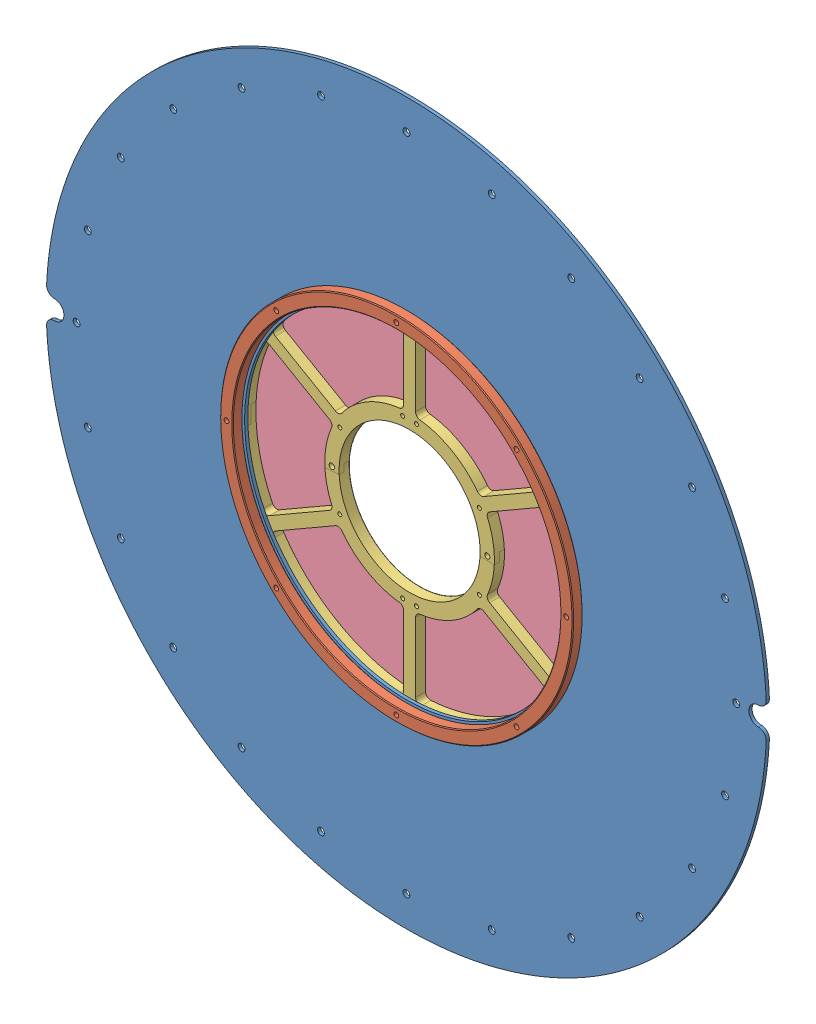
SolidWorks assembly IDS OSC Stiffener (West) ASSY, configuration Default. Lengths in mm.
Overall size (453.86 454.4 14.75).
6 component instances, 5 part files, 11 mates.
Components (placement in the parent):
- IDS OSC Stiffener (West)-1: IDS OSC Stiffener (West) [Default] at origin size (453.86 454.4 2)
- IDS Viton Disk-1: IDS Viton Disk [Default] at (0 0 -0.5) x (-0.55065 -0.834736 0) z (0 0 -1) (suppressed, hidden)
- IDS WSC Cooling Tube Support Ring-1: IDS WSC Cooling Tube Support Ring [Default] at (0 0 2) size (222.5 222.5 6.35)
- IDS WSC West Beampipe Support-1: IDS WSC West Beampipe Support [Default] at (0 0 -3.175) size (222 116.81 6.35)
- IDS WSC West Beampipe Support-2: IDS WSC West Beampipe Support [Default] at (0 0 -3.175) x (1 0 0) z (0 0 -1) size (222 116.81 6.35)
- IDS OSC Stiffener Air Cover-1: IDS OSC Stiffener Air Cover [Default] at origin size (222.5 222.5 0.05)
Mates (geometry in assembly coordinates):
- Coincident1: coincident anti-aligned: plane of IDS OSC Stiffener (West)-1 through (0 0 0) normal (0 0 -1); plane of IDS Viton Disk-1 through (-87.6473 57.8183 0) normal (0 0 1)
- Concentric1: concentric anti-aligned: cylinder of IDS OSC Stiffener (West)-1 through (0 0 2) axis (0 0 -1) radius 227.2; circle of IDS Viton Disk-1
- Coincident2: coincident anti-aligned: plane of IDS OSC Stiffener (West)-1 through (0 0 2) normal (0 0 1); plane of IDS WSC Cooling Tube Support Ring-1 through (0 0 2) normal (0 0 -1)
- Concentric2: concentric aligned: cylinder of IDS OSC Stiffener (West)-1 through (0 0 2) axis (0 0 -1) radius 227.2; cylinder of IDS WSC Cooling Tube Support Ring-1 through (0 0 8.35) axis (0 0 -1) radius 103.25
- Coincident3: coincident aligned: plane of IDS WSC West Beampipe Support-1 through (0 0 -3.175) normal (1 0 0); plane of assembly through (0 0 0) normal (1 0 0)
- Coincident4: coincident anti-aligned: plane of IDS OSC Stiffener (West)-1 through (0 0 0) normal (0 0 -1); plane of IDS WSC West Beampipe Support-1 through (0 -244.3414 0) normal (0 0 1)
- Coincident6: coincident aligned: plane of IDS WSC West Beampipe Support-1 through (0 0 -3.175) normal (0 1 0); plane of assembly through (0 0 0) normal (0 1 0)
- Coincident7: coincident anti-aligned: plane of IDS OSC Stiffener (West)-1 through (0 0 0) normal (0 0 -1); plane of IDS WSC West Beampipe Support-2 through (0 244.3414 0) normal (0 0 1)
- Coincident8: coincident anti-aligned: plane of IDS WSC West Beampipe Support-2 through (0 0 -3.175) normal (0 -1 0); plane of assembly through (0 0 0) normal (0 1 0)
- Coincident9: coincident aligned: plane of IDS WSC West Beampipe Support-2; plane of assembly through (0 0 0) normal (1 0 0)
- Coincident10: coincident aligned: plane of IDS WSC Cooling Tube Support Ring-1 through (0 0 2) normal (1 0 0); plane of assembly through (0 0 0) normal (1 0 0)
